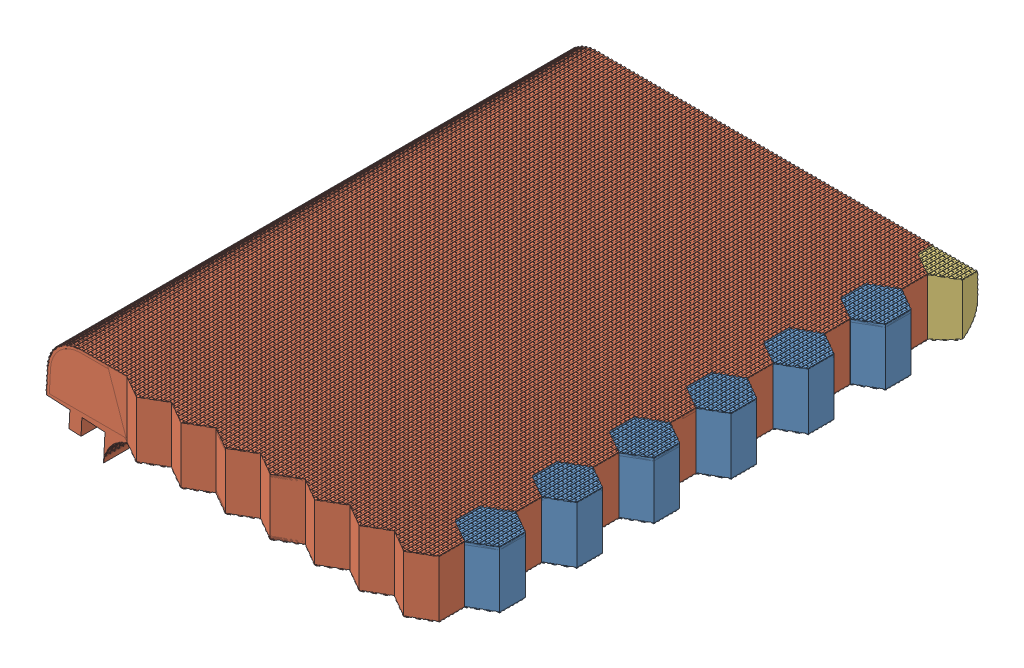
SolidWorks assembly C_assy_fix_half_hexCut_4of4, configuration Default. Lengths in mm.
Overall size (172.4 37.29 224.83).
8 component instances, 3 part files, 4 mates.
Components (placement in the parent):
- C_single_cell-1: C_single_cell [Default] at (-52.7417 -22.7177 -224.4942) size (116.22 24.09 21.35)
- C_assy_half_fix_part1of4-2: C_assy_half_fix_part1of4 [Default] at (-73.3217 -22.7177 -176.4298) size (163.15 37.29 220.95)
- C_single_cell-8: C_single_cell [Default] at (-52.7417 -22.7177 -256.5442) size (116.22 24.09 21.35)
- C_single_cell-9: C_single_cell [Default] at (-52.7417 -22.7177 -288.5942) size (116.22 24.09 21.35)
- C_single_cell-10: C_single_cell [Default] at (-52.7417 -22.7177 -320.6442) size (116.22 24.09 21.35)
- C_single_cell-11: C_single_cell [Default] at (-52.7417 -22.7177 -352.6942) size (116.22 24.09 21.35)
- C_single_cell-12: C_single_cell [Default] at (-52.7417 -22.7177 -384.7442) size (116.22 24.09 21.35)
- C_single_cell_cropped-1: C_single_cell_cropped [Default] at (-52.7412 -22.7177 -416.7517) size (116.22 24.09 16.53)
Mates (geometry in assembly coordinates):
- Coincident1: coincident anti-aligned: line of C_single_cell-1 through (-10.5678 -8.9744 -203.0027) axis (0 -1 0); line of C_assy_half_fix_part1of4-2 through (-10.5678 -32.1744 -203.0027) axis (0 1 0)
- Coincident2: coincident aligned: plane of C_single_cell-1 through (-7.0677 -8.5744 11.9163) normal (0 1 0); plane of C_assy_half_fix_part1of4-2 through (-7.3175 -8.5744 59.9807) normal (0 1 0)
- Coincident5: coincident aligned: line of C_assy_half_fix_part1of4-2 through (-10.5673 -29.9722 -384.5792) axis (0 1 0); line of C_single_cell_cropped-1 through (-10.5673 -32.1744 -384.5792) axis (0 1 0)
- Coincident6: coincident aligned: plane of C_assy_half_fix_part1of4-2 through (-10.9183 -8.5744 59.9807) normal (0 1 0); plane of C_single_cell_cropped-1 through (-1.6672 -8.5744 -180.3412) normal (0 1 0)
